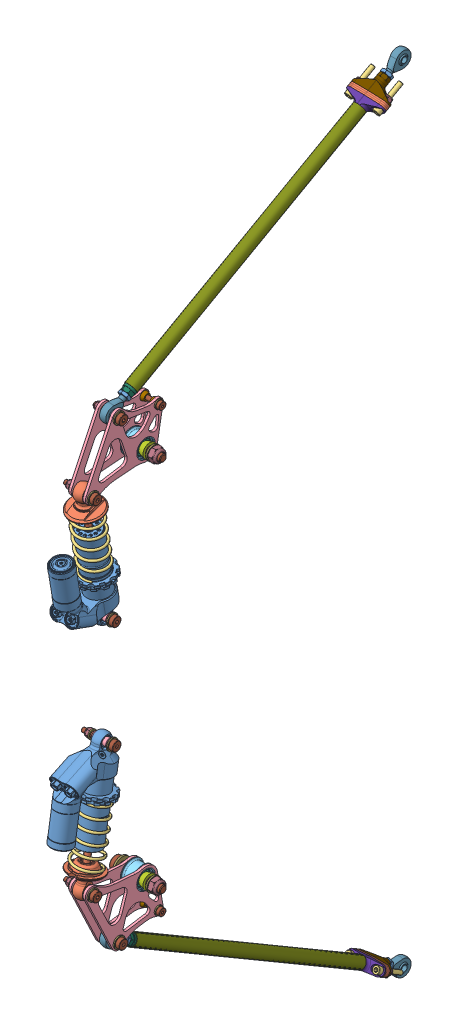
SolidWorks assembly PUTM-S-SF-DS, configuration Domyślna. Lengths in mm.
Overall size (69 1164.47 518.08).
110 component instances, 22 part files, 16 mates.
Components (placement in the parent):
- PUTM-S-SF-DS-Ohlines TTX25-Body-1: PUTM-S-SF-DS-Ohlines TTX25-Body [Default] at (10.0886 196.3852 582.3153) x (-0.998627 0.012225 0.050939) z (0.047909 -0.180167 0.982469) size (49.5 133.26 84.25)
- PUTM-S-SF-DS-Ohlines TTX25-Head-1: PUTM-S-SF-DS-Ohlines TTX25-Head [Default] at (9.5009 169.1049 577.3412) x (-0.991755 -0.001998 0.128136) z (0.126388 -0.18057 0.975408) size (46 110.31 45.56)
- PUTM-S-SF-DS-Spring-1: PUTM-S-SF-DS-Spring [Domyślna] at (8.8645 139.565 571.9552) x (0.984871 -0.051391 0.165493) z (-0.171988 -0.173114 0.969769) size (39.96 93.9 39.96)
- PUTM-S-SF-DS-Rocker-1: PUTM-S-SF-DS-Rocker [Domyślna] at (-1.5 0 0) size (69 714.03 147.28)
  - PUTM_S_SF_DS_Rockerplate-1: PUTM_S_SF_DS_Rockerplate [Default] at (14.7255 268.5661 513.4403) x (1 0 0) z (0 0.567564 0.823329) size (3.5 126.45 91.72)
  - PUTM_S_SF_DS_Rockerplate-2: PUTM_S_SF_DS_Rockerplate [Default] at (35.2255 268.5661 513.4403) x (1 0 0) z (0 0.567564 0.823329) size (3.5 126.45 91.72)
  - PUTM_S_SF_DS_Rockersleeve-4: PUTM_S_SF_DS_Rockersleeve [Domyślna] at (12.6854 268.5661 513.4403) x (1 0 0) z (0 0.045436 -0.998967) size (24 33 33)
  - PUTM-S-SF-DS-NKIB 5901-1: PUTM-S-SF-DS-NKIB 5901 [Domyślna] at (4.6854 268.5661 513.4403) x (1 0 0) z (0 0.01484 0.99989) size (17.5 24 24)
  - PUTM-S-SF-Rocker-MushRocker-5: PUTM-S-SF-Rocker-MushRocker [Domyślna] at (30.1854 268.5661 513.4403) x (-1 0 0) z (0 0.985233 0.171218) size (8 20 20)
  - PUTM-S-SF-Rocker-MushRocker_long-2: PUTM-S-SF-Rocker-MushRocker_long [Domyślna] at (-4.8146 268.5661 513.4403) x (1 0 0) z (0 0 1) size (9.5 20 20)
  - PUTM-S-Mush-1: PUTM-S-Mush [8x2] at (4.1854 326.5148 552.708) x (1 0 0) z (0 -0.21344 0.976956) size (2 12 12)
  - PUTM-S-Mush-2: PUTM-S-Mush [8x2] at (21.1854 326.5148 552.708) x (-1 0 0) z (0 -0.11515 0.993348) size (2 12 12)
  - PUTM-S-Mush-4: PUTM-S-Mush [6x4.5] at (21.1854 315.2834 495.6219) x (-1 0 0) z (0 0.027421 0.999624) size (4.5 12 12)
  - PUTM-S-Mush-3: PUTM-S-Mush [6x4.5] at (4.1854 315.2834 495.6219) x (1 0 0) z (0 0 1) size (4.5 12 12)
  - PUTM-S-SF-DS-Seger-1: PUTM-S-SF-DS-Seger [24 mm] at (4.6854 268.5661 513.4403) x (0 0.12945 0.991586) z (-1 0 0) size (25.2 25.11 1.2)
  - PUTM-FT-ELESA_ISO7379-1: PUTM-FT-ELESA_ISO7379 [8-M6-25] at (31.7854 326.5148 552.708) x (1 0 0) z (0 0.616334 0.787485) size (41.5 13 13)
  - PUTM-FT-FABORY_ISO7089-1: PUTM-FT-FABORY_ISO7089 [M8 [38093.080.001]] at (24.6854 326.5148 552.708) x (0 -0.947466 -0.319858) z (1 0 0) size (16 16 1.6)
  - PUTM-FT-FABORY_ISO7089-2: PUTM-FT-FABORY_ISO7089 [M6 [38093.060.001]] at (-0.9146 326.5148 552.708) x (0 0.510535 -0.859857) z (1 0 0) size (12 12 1.6)
  - PUTM-FT-FABORY_DIN985-1: PUTM-FT-FABORY_DIN985 [M6 [12348.060.001]] at (-0.9146 326.5148 552.708) x (0 0.291071 0.956701) z (-1 0 0) size (11.9 10.35 6.18)
  - PUTM-FT-ELESA_ISO7379-2: PUTM-FT-ELESA_ISO7379 [6-M5-25] at (30.7854 315.2834 495.6219) x (1 0 0) z (0 0.899221 0.437495) size (39 10 10)
  - PUTM-FT-FABORY_ISO7089-3: PUTM-FT-FABORY_ISO7089 [M6 [38093.060.001]] at (26.2854 315.2834 495.6219) x (0 -0.694708 -0.719291) z (-1 0 0) size (12 12 1.6)
  - PUTM-FT-FABORY_ISO7089-4: PUTM-FT-FABORY_ISO7089 [M6 [38093.060.001]] at (0.6854 315.2834 495.6219) x (0 -0.008303 -0.999966) z (-1 0 0) size (12 12 1.6)
  - PUTM-FT-FABORY_DIN985-2: PUTM-FT-FABORY_DIN985 [M5 [12348.050.001]] at (-0.9146 315.2834 495.6219) x (0 -0.96841 0.249362) z (-1 0 0) size (9.51 8.27 5.13)
  - PUTM-FT-ELESA_ISO7379-3: PUTM-FT-ELESA_ISO7379 [8-M6-30] at (33.2854 247.2979 591.5983) x (1 0 0) z (0 -0.758212 0.652008) size (46.5 13 13)
  - PUTM-FT-FABORY_ISO7089-5: PUTM-FT-FABORY_ISO7089 [M6 [38093.060.001]] at (-0.9146 247.2979 591.5983) x (0 0.756021 0.654548) z (-1 0 0) size (12 12 1.6)
  - PUTM-FT-FABORY_ISO7089-6: PUTM-FT-FABORY_ISO7089 [M8 [38093.080.001]] at (26.1854 247.2979 591.5983) x (0 0.88573 0.464201) z (1 0 0) size (16 16 1.6)
  - PUTM-FT-FABORY_DIN985-3: PUTM-FT-FABORY_DIN985 [M6 [12348.060.001]] at (-2.5146 247.2979 591.5983) x (0 0.369355 -0.929288) z (-1 0 0) size (11.9 10.35 6.18)
  - PUTM-FT-ELESA_ISO7379-10: PUTM-FT-ELESA_ISO7379 [12-M10-45] at (-19.3146 268.5661 513.4403) x (-1 0 0) z (0 0.653245 0.757146) size (69 18 18)
  - PUTM-FT-FABORY_ISO7089-19: PUTM-FT-FABORY_ISO7089 [M12 [38093.120.001]] at (-8.8146 268.5661 513.4403) x (0 0.487973 0.872859) z (-1 0 0) size (24 24 2.5)
  - PUTM-FT-FABORY_ISO7089-20: PUTM-FT-FABORY_ISO7089 [M10 [38093.100.001]] at (36.1854 268.5661 513.4403) x (0 -0.102877 0.994694) z (-1 0 0) size (20 20 2)
  - PUTM-FT-FABORY_DIN985-10: PUTM-FT-FABORY_DIN985 [M10 [12348.100.001]] at (36.1854 268.5661 513.4403) x (0 -0.924225 -0.381849) z (1 0 0) size (20.27 17.64 10.37)
  - PUTM-FT-FABORY_ISO7089-23: PUTM-FT-FABORY_ISO7089 [M8 [38093.080.001]] at (0.6854 247.2979 591.5983) x (0 0.385787 0.922588) z (-1 0 0) size (16 16 1.6)
  - PUTM-S-SF-DS-Seger-2: PUTM-S-SF-DS-Seger [24 mm] at (3.4854 -268.5661 513.4403) x (0 -0.12945 0.991586) z (1 0 0) size (25.2 25.11 1.2)
  - PUTM-S-SF-DS-NKIB 5901-2: PUTM-S-SF-DS-NKIB 5901 [Domyślna] at (4.6854 -268.5661 513.4403) x (1 0 0) z (0 0.01484 -0.99989) size (17.5 24 24)
  - PUTM-S-Mush-9: PUTM-S-Mush [8x2] at (21.1854 -326.5148 552.708) x (-1 0 0) z (0 -0.11515 -0.993348) size (2 12 12)
  - PUTM_S_SF_DS_Rockersleeve-6: PUTM_S_SF_DS_Rockersleeve [Domyślna] at (12.6854 -268.5661 513.4403) x (1 0 0) z (0 0.045436 0.998967) size (24 33 33)
  - PUTM-S-Mush-10: PUTM-S-Mush [6x4.5] at (21.1854 -315.2834 495.6219) x (-1 0 0) z (0 0.027421 -0.999624) size (4.5 12 12)
  - PUTM-S-Mush-11: PUTM-S-Mush [6x4.5] at (4.1854 -315.2834 495.6219) x (1 0 0) z (0 0 -1) size (4.5 12 12)
  - PUTM-S-Mush-12: PUTM-S-Mush [8x2] at (4.1854 -326.5148 552.708) x (1 0 0) z (0 -0.21344 -0.976956) size (2 12 12)
  - PUTM-FT-ELESA_ISO7379-7: PUTM-FT-ELESA_ISO7379 [8-M6-30] at (33.2854 -247.2979 591.5983) x (1 0 0) z (0 -0.758212 -0.652008) size (46.5 13 13)
  - PUTM-FT-FABORY_ISO7089-13: PUTM-FT-FABORY_ISO7089 [M6 [38093.060.001]] at (24.6854 -315.2834 495.6219) x (0 0.694708 -0.719291) z (1 0 0) size (12 12 1.6)
  - PUTM-FT-FABORY_ISO7089-14: PUTM-FT-FABORY_ISO7089 [M6 [38093.060.001]] at (0.6854 -326.5148 552.708) x (0 -0.510535 -0.859857) z (-1 0 0) size (12 12 1.6)
  - PUTM-FT-FABORY_DIN985-7: PUTM-FT-FABORY_DIN985 [M6 [12348.060.001]] at (-0.9146 -326.5148 552.708) x (0 0.291071 -0.956701) z (-1 0 0) size (11.9 10.35 6.18)
  - PUTM-FT-FABORY_ISO7089-15: PUTM-FT-FABORY_ISO7089 [M6 [38093.060.001]] at (-2.5146 -247.2979 591.5983) x (0 -0.756021 0.654548) z (1 0 0) size (12 12 1.6)
  - PUTM-FT-FABORY_DIN985-8: PUTM-FT-FABORY_DIN985 [M5 [12348.050.001]] at (-0.9146 -315.2834 495.6219) x (0 -0.96841 -0.249362) z (-1 0 0) size (9.51 8.27 5.13)
  - PUTM-FT-ELESA_ISO7379-8: PUTM-FT-ELESA_ISO7379 [8-M6-25] at (31.7854 -326.5148 552.708) x (1 0 0) z (0 0.616334 -0.787485) size (41.5 13 13)
  - PUTM-FT-ELESA_ISO7379-9: PUTM-FT-ELESA_ISO7379 [6-M5-25] at (30.7854 -315.2834 495.6219) x (1 0 0) z (0 0.899221 -0.437495) size (39 10 10)
  - PUTM_S_SF_DS_Rockerplate-5: PUTM_S_SF_DS_Rockerplate [Default] at (10.6453 -268.5661 513.4403) x (-1 0 0) z (0 -0.567564 0.823329) size (3.5 126.45 91.72)
  - PUTM-FT-FABORY_DIN985-9: PUTM-FT-FABORY_DIN985 [M6 [12348.060.001]] at (-2.5146 -247.2979 591.5983) x (0 0.369355 0.929288) z (-1 0 0) size (11.9 10.35 6.18)
  - PUTM-FT-FABORY_ISO7089-16: PUTM-FT-FABORY_ISO7089 [M8 [38093.080.001]] at (27.7854 -247.2979 591.5983) x (0 -0.88573 0.464201) z (-1 0 0) size (16 16 1.6)
  - PUTM-FT-FABORY_ISO7089-17: PUTM-FT-FABORY_ISO7089 [M6 [38093.060.001]] at (-0.9146 -315.2834 495.6219) x (0 0.008303 -0.999966) z (1 0 0) size (12 12 1.6)
  - PUTM-FT-FABORY_ISO7089-18: PUTM-FT-FABORY_ISO7089 [M8 [38093.080.001]] at (26.2854 -326.5148 552.708) x (0 0.947466 -0.319858) z (-1 0 0) size (16 16 1.6)
  - PUTM_S_SF_DS_Rockerplate-6: PUTM_S_SF_DS_Rockerplate [Default] at (-9.8547 -268.5661 513.4403) x (-1 0 0) z (0 -0.567564 0.823329) size (3.5 126.45 91.72)
  - PUTM-FT-ELESA_ISO7379-11: PUTM-FT-ELESA_ISO7379 [12-M10-45] at (-19.3146 -268.5661 513.4403) x (-1 0 0) z (0 0.653245 -0.757146) size (69 18 18)
  - PUTM-FT-FABORY_ISO7089-21: PUTM-FT-FABORY_ISO7089 [M12 [38093.120.001]] at (-11.3146 -268.5661 513.4403) x (0 -0.487973 0.872859) z (1 0 0) size (24 24 2.5)
  - PUTM-FT-FABORY_ISO7089-22: PUTM-FT-FABORY_ISO7089 [M10 [38093.100.001]] at (34.1854 -268.5661 513.4403) x (0 0.102877 0.994694) z (1 0 0) size (20 20 2)
  - PUTM-FT-FABORY_DIN985-11: PUTM-FT-FABORY_DIN985 [M10 [12348.100.001]] at (36.1854 -268.5661 513.4403) x (0 -0.924225 0.381849) z (1 0 0) size (20.27 17.64 10.37)
  - PUTM-S-SF-Rocker-MushRocker_long-4: PUTM-S-SF-Rocker-MushRocker_long [Domyślna] at (-4.8146 -268.5661 513.4403) x (1 0 0) z (0 0 -1) size (9.5 20 20)
  - PUTM-S-SF-Rocker-MushRocker-6: PUTM-S-SF-Rocker-MushRocker [Domyślna] at (30.1854 -268.5661 513.4403) x (-1 0 0) z (0 0.985233 -0.171218) size (8 20 20)
  - PUTM-FT-FABORY_ISO7089-24: PUTM-FT-FABORY_ISO7089 [M8 [38093.080.001]] at (-0.9146 -247.2979 591.5983) x (0 -0.385787 0.922588) z (1 0 0) size (16 16 1.6)
- PUTM-S-SF-DS-Pushrod-1: PUTM-S-SF-DS-Pushrod [Domyślna] at origin size (55.39 1164.47 444.32)
  - PUTM-S-rodend-1: PUTM-S-rodend [8mm] at (16.1142 544.6228 177.5261) x (0.999845 -0.01736 0.002913) z (0.013544 0.864372 0.502671) size (12 54 24)
  - PUTM-S-Insert-M8-1: PUTM-S-Insert-M8 [M8] at (11.5338 341.9347 526.1831) x (0.011357 0.502552 -0.864472) z (0.972059 0.197164 0.127389) size (38.3 16.51 15.5)
  - PUTM-S-SF-DS-1: PUTM-S-SF-DS [Domyślna] at (15.8235 531.7571 199.6573) x (0.870419 0.420563 0.255925) z (-0.011357 -0.502552 0.864472) size (16.7 16.7 375.94)
  - PUTM-S-SF-DS-Insert-shims-1: PUTM-S-SF-DS-Insert-shims [Domyślna] at (15.9689 538.1934 188.5858) x (-0.999648 0.02645 0.002244) z (0.023993 0.864142 0.502675) size (54 51.59 16.38)
  - PUTM-S-SF-DS-Insert-shims-2-1: PUTM-S-SF-DS-Insert-shims-2 [M8] at (16.037 541.2087 183.399) x (0.999648 -0.02645 -0.002244) z (0.023993 0.864142 0.502675) size (54 25 22.85)
  - PUTM-S-DS-DIN-EN-ISO-4035-1: PUTM-S-DS-DIN-EN-ISO-4035 [M8_low] at (16.3664 555.7827 158.3293) x (0.730738 0.585963 0.350243) z (-0.011357 -0.502552 0.864472) size (13 15.01 4)
  - PUTM-S-SF-DS-Shims-1: PUTM-S-SF-DS-Shims [2mm] at (15.9916 539.1985 186.8569) x (0.999648 -0.02645 -0.002244) z (-0.011357 -0.502552 0.864472) size (54 15.5 2)
  - PUTM-S-SF-DS-Shims-2: PUTM-S-SF-DS-Shims [2mm] at (16.0143 540.2036 185.1279) x (0.999648 -0.02645 -0.002244) z (-0.011357 -0.502552 0.864472) size (54 15.5 2)
  - PUTM-S-SF-DS-Shims-3: PUTM-S-SF-DS-Shims [2mm] at (16.037 541.2087 183.399) x (0.999648 -0.02645 -0.002244) z (-0.011357 -0.502552 0.864472) size (54 15.5 2)
  - PUTM-S-rodend-2: PUTM-S-rodend [8mm] at (11.6624 347.6215 516.4009) x (0.999727 -0.023347 -0.000309) z (-0.020338 -0.864233 -0.50268) size (12 54 24)
  - PUTM-S-DS-DIN-EN-ISO-4035-2: PUTM-S-DS-DIN-EN-ISO-4035 [M8_low] at (11.4737 339.2712 530.7648) x (0.999931 -0.003061 0.011357) z (-0.011357 -0.502552 0.864472) size (13 15.01 4)
  - PUTM-FT-FABORY_ISO912-2: PUTM-FT-FABORY_ISO912 [M6x35 [07071.060.035]] at (35.871 533.644 195.4567) x (-0.011357 -0.502552 0.864472) z (-0.998923 -0.033187 -0.032416) size (41 10 10)
  - PUTM-FT-FABORY_ISO912-3: PUTM-FT-FABORY_ISO912 [M6x35 [07071.060.035]] at (-4.1149 534.702 195.5465) x (-0.011357 -0.502552 0.864472) z (0.178681 -0.851633 -0.492741) size (41 10 10)
  - PUTM-FT-FABORY_DIN985-1: PUTM-FT-FABORY_DIN985 [M6 [12348.060.001]] at (36.0527 541.6848 181.6251) x (0.999697 -0.024571 -0.001151) z (0.011357 0.502552 -0.864472) size (11.9 10.35 6.18)
  - PUTM-FT-FABORY_DIN985-2: PUTM-FT-FABORY_DIN985 [M6 [12348.060.001]] at (-3.9332 542.7428 181.7149) x (0.981398 -0.171296 -0.086688) z (0.011357 0.502552 -0.864472) size (11.9 10.35 6.18)
  - PUTM-FT-FABORY_DIN985-3: PUTM-FT-FABORY_DIN985 [M6 [12348.060.001]] at (-3.9332 -542.7428 181.7149) x (-0.981398 -0.171296 0.086688) z (0.011357 -0.502552 -0.864472) size (11.9 10.35 6.18)
  - PUTM-FT-FABORY_ISO912-4: PUTM-FT-FABORY_ISO912 [M6x35 [07071.060.035]] at (-4.1149 -534.702 195.5465) x (-0.011357 0.502552 0.864472) z (-0.178681 -0.851633 0.492741) size (41 10 10)
  - PUTM-S-rodend-3: PUTM-S-rodend [8mm] at (11.6624 -347.6215 516.4009) x (0.999727 0.023347 -0.000309) z (0.020338 -0.864233 0.50268) size (12 54 24)
  - PUTM-S-SF-DS-Shims-4: PUTM-S-SF-DS-Shims [2mm] at (15.9916 -539.1985 186.8569) x (0.999648 0.02645 -0.002244) z (0.011357 -0.502552 -0.864472) size (54 15.5 2)
  - PUTM-S-SF-DS-Shims-5: PUTM-S-SF-DS-Shims [2mm] at (15.9689 -538.1934 188.5858) x (0.999648 0.02645 -0.002244) z (0.011357 -0.502552 -0.864472) size (54 15.5 2)
  - PUTM-S-SF-DS-Insert-shims-2-2: PUTM-S-SF-DS-Insert-shims-2 [M8] at (16.037 -541.2087 183.399) x (0.999648 0.02645 -0.002244) z (-0.023993 0.864142 -0.502675) size (54 25 22.85)
  - PUTM-S-Insert-M8-2: PUTM-S-Insert-M8 [M8] at (11.5338 -341.9347 526.1831) x (0.011357 -0.502552 -0.864472) z (-0.972059 0.197164 -0.127389) size (38.3 16.51 15.5)
  - PUTM-S-SF-DS-Insert-shims-2: PUTM-S-SF-DS-Insert-shims [Domyślna] at (15.9689 -538.1934 188.5858) x (-0.999648 -0.02645 0.002244) z (-0.023993 0.864142 -0.502675) size (54 51.59 16.38)
  - PUTM-FT-FABORY_DIN985-4: PUTM-FT-FABORY_DIN985 [M6 [12348.060.001]] at (36.0527 -541.6848 181.6251) x (-0.999697 -0.024571 0.001151) z (0.011357 -0.502552 -0.864472) size (11.9 10.35 6.18)
  - PUTM-S-DS-DIN-EN-ISO-4035-3: PUTM-S-DS-DIN-EN-ISO-4035 [M8_low] at (11.4282 -337.261 534.2227) x (0.999931 0.003061 0.011357) z (0.011357 -0.502552 -0.864472) size (13 15.01 4)
  - PUTM-S-SF-DS-Shims-6: PUTM-S-SF-DS-Shims [2mm] at (16.0143 -540.2036 185.1279) x (0.999648 0.02645 -0.002244) z (0.011357 -0.502552 -0.864472) size (54 15.5 2)
  - PUTM-S-SF-DS-2: PUTM-S-SF-DS [Domyślna] at (11.5818 -344.0547 522.5364) x (0.870419 -0.420563 0.255925) z (0.011357 -0.502552 -0.864472) size (16.7 16.7 375.94)
  - PUTM-FT-FABORY_ISO912-5: PUTM-FT-FABORY_ISO912 [M6x35 [07071.060.035]] at (35.871 -533.644 195.4567) x (-0.011357 0.502552 0.864472) z (0.998923 -0.033187 0.032416) size (41 10 10)
  - PUTM-S-rodend-4: PUTM-S-rodend [8mm] at (16.1142 -544.6228 177.5261) x (0.999845 0.01736 0.002913) z (-0.013544 0.864372 -0.502671) size (12 54 24)
  - PUTM-S-DS-DIN-EN-ISO-4035-4: PUTM-S-DS-DIN-EN-ISO-4035 [M8_low] at (16.321 -553.7725 161.7872) x (0.730738 -0.585963 0.350243) z (0.011357 -0.502552 -0.864472) size (13 15.01 4)
- PUTM-S-SF-DS-Ohlines TTX25-Body-6: PUTM-S-SF-DS-Ohlines TTX25-Body [Default] at (10.1664 -197.3084 582.9318) x (0.998627 0.012225 -0.050939) z (0.047909 0.180167 0.982469) size (49.5 133.26 84.25)
- PUTM-S-SF-DS-Ohlines TTX25-Head-6: PUTM-S-SF-DS-Ohlines TTX25-Head [Default] at (9.5571 -169.0246 577.7748) x (-0.991755 0.001998 0.128136) z (-0.126388 -0.18057 -0.975408) size (46 110.31 45.56)
- PUTM-S-SF-DS-Spring-5: PUTM-S-SF-DS-Spring [Domyślna] at (10.7058 -225.0356 587.5392) x (-0.984871 -0.051391 -0.165493) z (0.171988 -0.173114 -0.969769) size (39.96 93.9 39.96)
- PUTM-S-Mush-1: PUTM-S-Mush [8x5.75] at (2.6854 247.2979 591.5983) x (1 0 0) z (0 0 1) size (5.75 12 12)
- PUTM-S-Mush-2: PUTM-S-Mush [8x5.75] at (19.6854 247.2979 591.5983) x (-1 0 0) z (0 -0.789747 0.613433) size (5.75 12 12)
- PUTM-S-SF-DS-DamperMush-1: PUTM-S-SF-DS-DamperMush [Domyślna] at (-2.4159 -77.9881 561.2132) x (0.998627 0.012225 -0.050939) z (0.051909 -0.361782 0.930816) size (6 12 12)
- PUTM-S-SF-DS-DamperMush-2: PUTM-S-SF-DS-DamperMush [Domyślna] at (17.5566 -77.7436 560.1944) x (-0.998627 -0.012225 0.050939) z (-0.014838 -0.866556 -0.49886) size (6 12 12)
- PUTM-S-Mush-3: PUTM-S-Mush [8x5.75] at (2.6854 -247.2979 591.5983) x (1 0 0) z (0 0 -1) size (5.75 12 12)
- PUTM-S-Mush-4: PUTM-S-Mush [8x5.75] at (19.6854 -247.2979 591.5983) x (-1 0 0) z (0 -0.789747 -0.613433) size (5.75 12 12)
- PUTM-FT-ELESA_ISO7379-1: PUTM-FT-ELESA_ISO7379 [8-M6-30] at (27.6078 77.6205 559.6817) x (0.998627 -0.012225 -0.050939) z (-0.047626 -0.616858 -0.785632) size (46.5 13 13)
- PUTM-FT-FABORY_ISO7089-1: PUTM-FT-FABORY_ISO7089 [M8 [38093.080.001]] at (22.1153 77.6878 559.9618) x (0.051177 0.020014 0.998489) z (-0.998627 0.012225 0.050939) size (16 16 1.6)
- PUTM-FT-FABORY_ISO7089-2: PUTM-FT-FABORY_ISO7089 [M6 [38093.060.001]] at (-5.4468 78.0252 561.3678) x (0.051081 0.011617 0.998627) z (-0.998627 0.012225 0.050939) size (12 12 1.6)
- PUTM-FT-FABORY_DIN985-1: PUTM-FT-FABORY_DIN985 [M6 [12348.060.001]] at (-7.0446 78.0448 561.4493) x (0.050543 -0.030805 0.998247) z (-0.998627 0.012225 0.050939) size (11.9 10.35 6.18)
- PUTM-FT-ELESA_ISO7379-2: PUTM-FT-ELESA_ISO7379 [8-M6-30] at (27.6078 -77.6205 559.6817) x (0.998627 0.012225 -0.050939) z (0.047626 -0.616858 0.785632) size (46.5 13 13)
- PUTM-FT-FABORY_ISO7089-3: PUTM-FT-FABORY_ISO7089 [M8 [38093.080.001]] at (20.5175 -77.7073 560.0433) x (0.051177 -0.020014 0.998489) z (0.998627 0.012225 -0.050939) size (16 16 1.6)
- PUTM-FT-FABORY_DIN985-2: PUTM-FT-FABORY_DIN985 [M6 [12348.060.001]] at (-7.0446 -78.0448 561.4493) x (-0.050543 -0.030805 -0.998247) z (-0.998627 -0.012225 0.050939) size (11.9 10.35 6.18)
- PUTM-FT-FABORY_ISO7089-4: PUTM-FT-FABORY_ISO7089 [M6 [38093.060.001]] at (-7.0446 -78.0448 561.4493) x (0.051081 -0.011617 0.998627) z (0.998627 0.012225 -0.050939) size (12 12 1.6)
- PUTM-S-SF-DS-DamperMush-3: PUTM-S-SF-DS-DamperMush [Domyślna] at (17.5566 77.7436 560.1944) x (-0.998627 0.012225 0.050939) z (0.014838 -0.866556 0.49886) size (6 12 12)
- PUTM-S-SF-DS-DamperMush-4: PUTM-S-SF-DS-DamperMush [Domyślna] at (-2.4159 77.9881 561.2132) x (0.998627 -0.012225 -0.050939) z (-0.051909 -0.361782 -0.930816) size (6 12 12)
Mates (geometry in assembly coordinates):
- Koncentryczne7: concentric anti-aligned: cylinder of PUTM-S-SF-DS-Ohlines TTX25-Body-1 through (9.7305 179.7631 579.2846) axis (-0.021188 -0.98356 -0.179334) radius 6; cylinder of PUTM-S-SF-DS-Ohlines TTX25-Head-1 through (10.9629 236.9705 589.7153) axis (0.021188 0.98356 0.179334) radius 3.9935
- Koncentryczne8: concentric anti-aligned: circle of PUTM-S-SF-DS-Ohlines TTX25-Body-6; cylinder of PUTM-S-SF-DS-Ohlines TTX25-Head-6 through (11.0191 -236.8903 590.1489) axis (0.021188 -0.98356 0.179334) radius 3.9935
- Koncentryczne9: concentric aligned: cylinder of PUTM-S-SF-DS-Rocker-1/PUTM-FT-ELESA_ISO7379-3 through (31.7854 247.2979 591.5983) axis (-1 0 0) radius 4; cylinder of PUTM-S-Mush-1 through (2.6854 247.2979 591.5983) axis (-1 0 0) radius 4
- Wspólnie2: coincident anti-aligned: plane of PUTM-S-SF-DS-Rocker-1/PUTM_S_SF_DS_Rockerplate-1 through (2.6854 268.5661 513.4403) normal (1 0 0); plane of PUTM-S-Mush-1 through (2.6854 253.2979 591.5983) normal (-1 0 0)
- Koncentryczne10: concentric anti-aligned: cylinder of PUTM-S-SF-DS-Rocker-1/PUTM-FT-ELESA_ISO7379-3 through (31.7854 247.2979 591.5983) axis (-1 0 0) radius 4; cylinder of PUTM-S-Mush-2 through (19.6854 247.2979 591.5983) axis (1 0 0) radius 4
- Wspólnie3: coincident anti-aligned: plane of PUTM-S-SF-DS-Rocker-1/PUTM_S_SF_DS_Rockerplate-2 through (19.6854 268.5661 513.4403) normal (-1 0 0); plane of PUTM-S-Mush-2 through (19.6854 243.6173 586.8598) normal (1 0 0)
- Koncentryczne11: concentric anti-aligned: cylinder of PUTM-S-SF-DS-Ohlines TTX25-Body-1 through (18.7143 77.7294 560.1353) axis (0.998627 -0.012225 -0.050939) radius 4; cylinder of PUTM-FT-ELESA_ISO7379-1 through (27.6078 77.6205 559.6817) axis (-0.998627 0.012225 0.050939) radius 4
- Koncentryczne12: concentric anti-aligned: cylinder of PUTM-FT-ELESA_ISO7379-1 through (27.6078 77.6205 559.6817) axis (-0.998627 0.012225 0.050939) radius 4; cylinder of PUTM-FT-FABORY_ISO7089-1 through (20.5175 77.7073 560.0433) axis (0.998627 -0.012225 -0.050939) radius 4.2
- Wspólnie4: coincident anti-aligned: plane of PUTM-FT-ELESA_ISO7379-1 through (22.2572 72.5724 563.9697) normal (-0.998627 0.012225 0.050939); plane of PUTM-FT-FABORY_ISO7089-1 through (22.1153 77.6878 559.9618) normal (0.998627 -0.012225 -0.050939)
- Koncentryczne13: concentric anti-aligned: cylinder of PUTM-FT-ELESA_ISO7379-1 through (27.6078 77.6205 559.6817) axis (-0.998627 0.012225 0.050939) radius 3; cylinder of PUTM-FT-FABORY_ISO7089-2 through (-7.0446 78.0448 561.4493) axis (0.998627 -0.012225 -0.050939) radius 3.2
- Koncentryczne14: concentric anti-aligned: cylinder of PUTM-FT-ELESA_ISO7379-1 through (27.6078 77.6205 559.6817) axis (-0.998627 0.012225 0.050939) radius 3; cylinder of PUTM-FT-FABORY_DIN985-1 through (-11.0391 78.0937 561.653) axis (0.998627 -0.012225 -0.050939) radius 3
- Wspólnie5: coincident anti-aligned: plane of PUTM-FT-FABORY_ISO7089-2 through (-7.0446 78.0448 561.4493) normal (-0.998627 0.012225 0.050939); plane of PUTM-FT-FABORY_DIN985-1 through (-7.0446 78.0448 561.4493) normal (0.998627 -0.012225 -0.050939)
- Koncentryczne15: concentric aligned: cylinder of PUTM-FT-ELESA_ISO7379-2 through (27.6078 -77.6205 559.6817) axis (-0.998627 -0.012225 0.050939) radius 4; cylinder of PUTM-S-SF-DS-DamperMush-1 through (-2.4159 -77.9881 561.2132) axis (-0.998627 -0.012225 0.050939) radius 4
- Wspólnie6: coincident anti-aligned: plane of PUTM-S-SF-DS-Ohlines TTX25-Body-6 through (3.5101 -73.7991 560.607) normal (-0.998627 -0.012225 0.050939); plane of PUTM-S-SF-DS-DamperMush-1 through (3.6111 -73.2538 562.7171) normal (0.998627 0.012225 -0.050939)
- Koncentryczne16: concentric anti-aligned: cylinder of PUTM-FT-ELESA_ISO7379-2 through (27.6078 -77.6205 559.6817) axis (-0.998627 -0.012225 0.050939) radius 4; cylinder of PUTM-S-SF-DS-DamperMush-2 through (17.5566 -77.7436 560.1944) axis (0.998627 0.012225 -0.050939) radius 4
- Wspólnie7: coincident anti-aligned: plane of PUTM-S-SF-DS-Ohlines TTX25-Body-6 through (11.4991 -73.7013 560.1995) normal (0.998627 0.012225 -0.050939); plane of PUTM-S-SF-DS-DamperMush-2 through (11.3136 -75.3223 556.1741) normal (-0.998627 -0.012225 0.050939)
